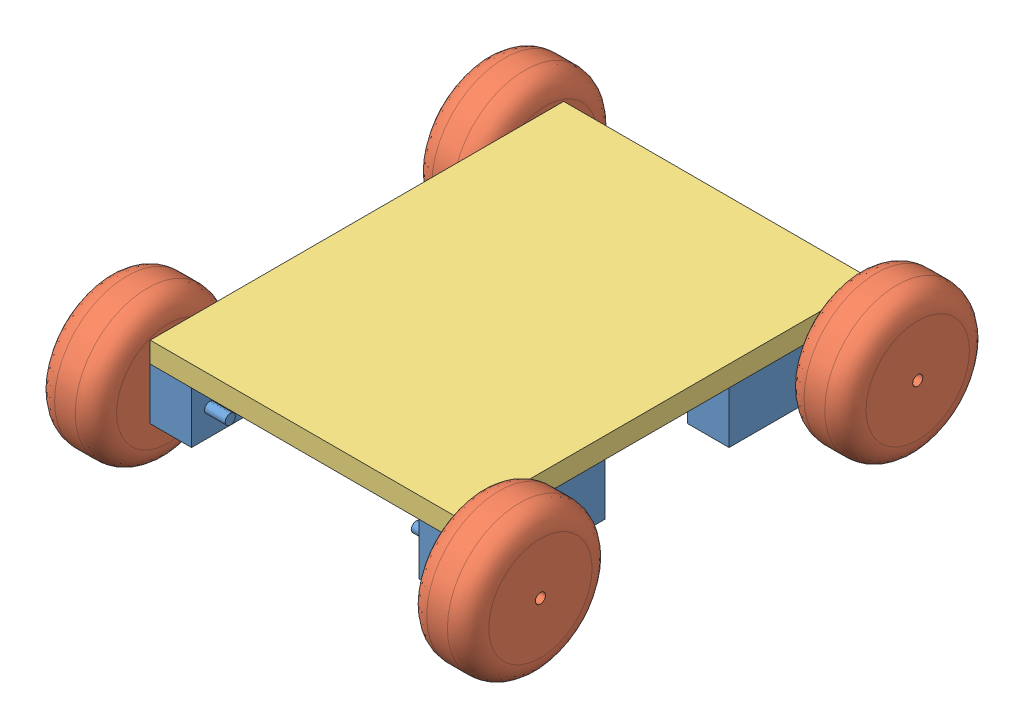
SolidWorks assembly Сборка1, configuration По умолчанию. Lengths in mm.
Overall size (210 74.6 257.1).
9 component instances, 3 part files, 24 mates.
Components (placement in the parent):
- двигатель-1: двигатель [По умолчанию] at origin size (40 25 70)
- колесо-1: колесо [По умолчанию] at (30 12.5 -61.25) x (-1 0 0) z (0 0.997679 0.068098) size (30 70 70)
- двигатель-2: двигатель [По умолчанию] at (-130 0 0) size (40 25 70)
- колесо-2: колесо [По умолчанию] at (-150 12.5 -61.25) x (-1 0 0) z (0 0.997679 0.068098) size (30 70 70)
- колесо-3: колесо [По умолчанию] at (-150 12.5 121.25) x (-1 0 0) z (0 0.997679 0.068098) size (30 70 70)
- двигатель-3: двигатель [По умолчанию] at (-150 0 60) x (-1 0 0) z (0 0 -1) size (40 25 70)
- колесо-4: колесо [По умолчанию] at (30 12.5 121.25) x (-1 0 0) z (0 0.997679 0.068098) size (30 70 70)
- двигатель-4: двигатель [По умолчанию] at (-20 0 60) x (-1 0 0) z (0 0 -1) size (40 25 70)
- доска-1: доска [По умолчанию] at (-150 25 130) size (150 10 200)
Mates (geometry in assembly coordinates):
- Заблокировать1: lock: unknown of двигатель-1; unknown of колесо-1
- Совпадение3: coincident anti-aligned: circle of двигатель-2; circle of колесо-2
- Совпадение7: coincident aligned: line of двигатель-1 through (0 25 -70) axis (-1 0 0); line of двигатель-2 through (-130 25 -70) axis (-1 0 0)
- Совпадение8: coincident aligned: line of двигатель-1 through (-20 25 0) axis (1 0 0); line of двигатель-2 through (-150 25 0) axis (1 0 0)
- Заблокировать3: lock: unknown of двигатель-2; unknown of колесо-2
- Заблокировать4: lock: unknown of двигатель-2; unknown of колесо-2
- Параллельность2: parallel anti-aligned: line of двигатель-2 through (-150 25 0) axis (1 0 0); line of двигатель-3 through (-130 25 60) axis (-1 0 0)
- Совпадение12: coincident aligned: plane of двигатель-2 through (-130 0 0) normal (0 -1 0); plane of двигатель-3 through (-150 0 60) normal (0 -1 0)
- Совпадение13: coincident aligned: plane of двигатель-2 through (-130 25 0) normal (1 0 0); plane of двигатель-3 through (-130 25 60) normal (1 0 0)
- Совпадение15: coincident anti-aligned: circle of колесо-3; circle of двигатель-3
- Заблокировать5: lock: unknown of колесо-3; unknown of двигатель-3
- Параллельность4: parallel anti-aligned: line of двигатель-3 through (-130 25 130) axis (0 0 -1); line of двигатель-4 through (-20 25 60) axis (0 0 1)
- Параллельность5: parallel anti-aligned: line of двигатель-1 through (-20 25 0) axis (1 0 0); line of двигатель-4 through (0 25 60) axis (-1 0 0)
- Совпадение18: coincident aligned: plane of двигатель-1 through (0 25 0) normal (0 1 0); plane of двигатель-4 through (-20 25 60) normal (0 1 0)
- Совпадение19: coincident aligned: plane of двигатель-3 through (-150 25 130) normal (0 0 1); plane of двигатель-4 through (-20 25 130) normal (0 0 1)
- Совпадение20: coincident aligned: plane of двигатель-1 through (-20 25 0) normal (-1 0 0); plane of двигатель-4 through (-20 25 60) normal (-1 0 0)
- Совпадение21: coincident aligned: circle of колесо-4; circle of двигатель-4
- Заблокировать6: lock: unknown of колесо-4; unknown of двигатель-4
- Заблокировать7: lock: unknown of колесо-4; unknown of двигатель-4
- Расстояние2: distance = 200 mm anti-aligned: plane of двигатель-3 through (-150 25 130) normal (0 0 1); plane of двигатель-2 through (-130 25 -70) normal (0 0 -1)
- Расстояние3: distance = 150 mm anti-aligned: plane of двигатель-2 through (-150 25 0) normal (-1 0 0); plane of двигатель-1 through (0 25 0) normal (1 0 0)
- Совпадение26: coincident aligned: line of двигатель-3 through (-150 25 130) axis (1 0 0); line of доска-1 through (-150 25 130) axis (1 0 0)
- Параллельность6: parallel aligned: line of двигатель-1 through (0 0 0) axis (0 0 -1); line of доска-1 through (0 25 130) axis (0 0 -1)
- Совпадение28: coincident aligned: plane of двигатель-4 through (0 25 60) normal (1 0 0); plane of доска-1 through (0 35 130) normal (1 0 0)
